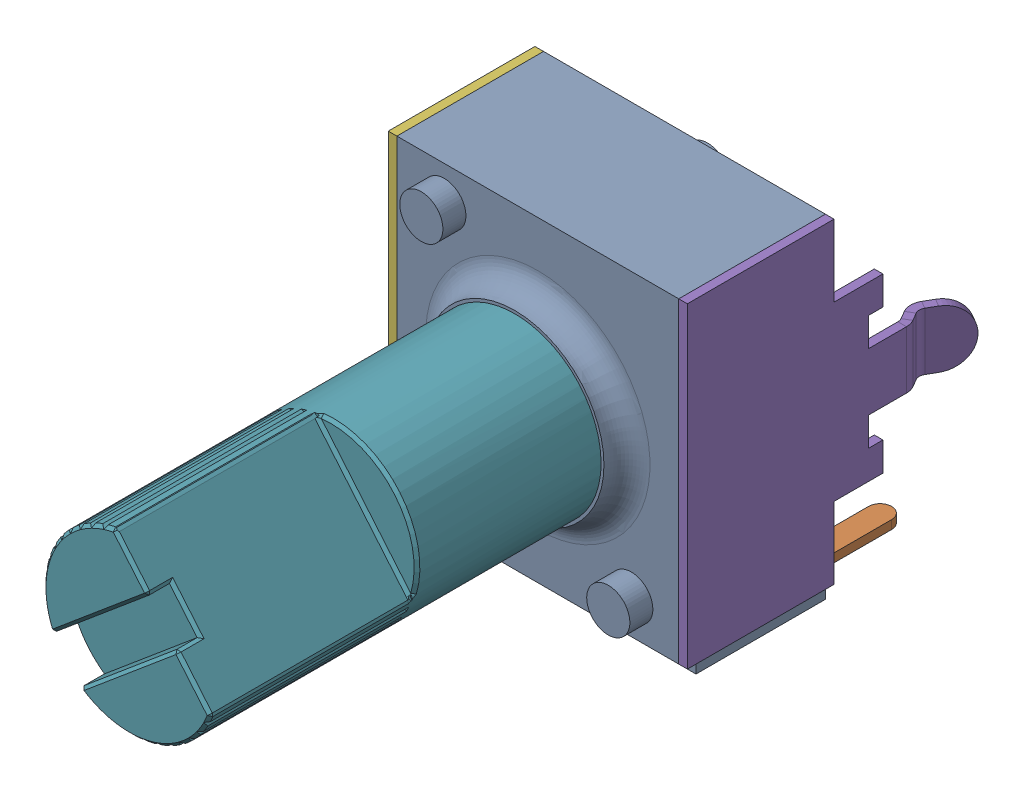
SolidWorks assembly R37_1.step, configuration Default. Lengths in mm.
Overall size (11.27 12.65 24.02).
7 component instances, 7 part files, 0 mates.
Components (placement in the parent):
- pot_1.step-3: pot_1.step [Default] at (355.95 288.1955 1.8) x (1 0 0) z (0 -1 0) size (9.8 6.7 11.6)
- pot-0_1.step-3: pot-0_1.step [Default] at (355.95 288.1955 1.8) x (1 0 0) z (0 -1 0) size (1.25 5.85 1.65)
- pot-1_1.step-3: pot-1_1.step [Default] at (355.95 288.1955 1.8) x (1 0 0) z (0 -1 0) size (1.25 5.85 1.65)
- pot-2_1.step-3: pot-2_1.step [Default] at (355.95 288.1955 1.8) x (1 0 0) z (0 -1 0) size (1.25 5.85 1.65)
- pot-3_1.step-3: pot-3_1.step [Default] at (355.95 288.1955 1.8) x (1 0 0) z (0 -1 0) size (1.02 9.82 11)
- pot-4_1.step-3: pot-4_1.step [Default] at (355.95 288.1955 1.8) x (1 0 0) z (0 -1 0) size (1.02 9.82 11)
- pot-5_1.step-3: pot-5_1.step [Default] at (355.95 288.1955 1.8) x (1 0 0) z (0 -1 0) size (6 14.2 6)
